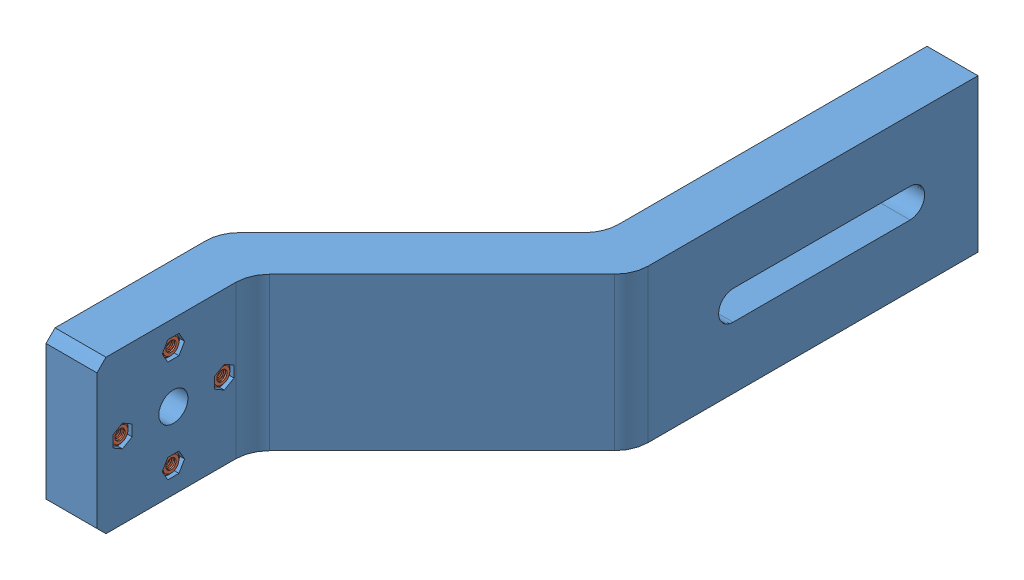
SolidWorks assembly stand_subassembly, configuration Default. Lengths in mm.
Overall size (71.57 45 202.78).
5 component instances, 2 part files, 12 mates.
Components (placement in the parent):
- Stand^stand_subassembly-1: Stand^stand_subassembly [Default] at (166.7875 84.0773 -187.1286) x (-1 0 0) z (0 0 -1) size (71.57 45 202.78) (virtual)
- M3 x 0.5 Hex Nut-1: M3 x 0.5 Hex Nut [90592A085] at (107.919 121.5773 -6.8468) x (0 -0.5 0.866025) z (0 0.866025 0.5) size (5.5 2.98 6.35)
- M3 x 0.5 Hex Nut-2: M3 x 0.5 Hex Nut [90592A085] at (107.919 91.5773 -6.8468) x (0 0.5 0.866025) z (0 0.866025 -0.5) size (5.5 2.98 6.35)
- M3 x 0.5 Hex Nut-3: M3 x 0.5 Hex Nut [90592A085] at (107.919 106.5773 -21.8468) x (0 -0.866025 0.5) z (0 0.5 0.866025) size (5.5 2.98 6.35)
- M3 x 0.5 Hex Nut-4: M3 x 0.5 Hex Nut [90592A085] at (107.919 106.5773 8.1532) x (0 0.866025 0.5) z (0 0.5 -0.866025) size (5.5 2.98 6.35)
Mates (geometry in assembly coordinates):
- Parallel14: parallel anti-aligned: plane of Stand^stand_subassembly_TSA3-1 through (106.719 124.4273 -5.2014) normal (0 -0.5 -0.866025); plane of M3 x 0.5 Hex Nut-1 through (109.119 124.3273 -5.2591) normal (0 0.5 0.866025)
- Parallel15: parallel anti-aligned: plane of Stand^stand_subassembly_TSA3-1 through (106.719 109.8682 8.1532) normal (0 -0.866025 -0.5); plane of M3 x 0.5 Hex Nut-4 through (109.119 109.7527 8.1532) normal (0 0.866025 0.5)
- Parallel16: parallel anti-aligned: plane of Stand^stand_subassembly_TSA3-1 through (106.719 94.4273 -5.2014) normal (0 -0.5 -0.866025); plane of M3 x 0.5 Hex Nut-2 through (109.119 94.3273 -5.2591) normal (0 0.5 0.866025)
- Parallel17: parallel anti-aligned: plane of Stand^stand_subassembly_TSA3-1 through (106.719 109.8682 -21.8468) normal (0 -0.866025 -0.5); plane of M3 x 0.5 Hex Nut-3 through (109.119 109.7527 -21.8468) normal (0 0.866025 0.5)
- Concentric58: concentric anti-aligned: circle of Stand^stand_subassembly_TSA2-1; circle of M3 x 0.5 Hex Nut-2
- Concentric59: concentric anti-aligned: circle of Stand^stand_subassembly_TSA2-1; circle of M3 x 0.5 Hex Nut-4
- Concentric60: concentric anti-aligned: circle of Stand^stand_subassembly_TSA2-1; circle of M3 x 0.5 Hex Nut-3
- Concentric61: concentric anti-aligned: circle of Stand^stand_subassembly_TSA2-1; circle of M3 x 0.5 Hex Nut-1
- Coincident182: coincident anti-aligned: plane of Stand^stand_subassembly_TSA3-1 through (106.719 84.0773 -187.1286) normal (1 0 0); plane of M3 x 0.5 Hex Nut-1 through (106.719 121.5773 -10.0222) normal (-1 0 0)
- Coincident183: coincident anti-aligned: plane of Stand^stand_subassembly_TSA3-1 through (106.719 84.0773 -187.1286) normal (1 0 0); plane of M3 x 0.5 Hex Nut-4 through (106.719 103.4018 8.1532) normal (-1 0 0)
- Coincident184: coincident anti-aligned: plane of Stand^stand_subassembly_TSA3-1 through (106.719 84.0773 -187.1286) normal (1 0 0); plane of M3 x 0.5 Hex Nut-3 through (106.719 108.165 -24.5968) normal (-1 0 0)
- Coincident185: coincident anti-aligned: plane of Stand^stand_subassembly_TSA3-1 through (106.719 84.0773 -187.1286) normal (1 0 0); plane of M3 x 0.5 Hex Nut-2 through (106.719 88.8273 -8.4345) normal (-1 0 0)
